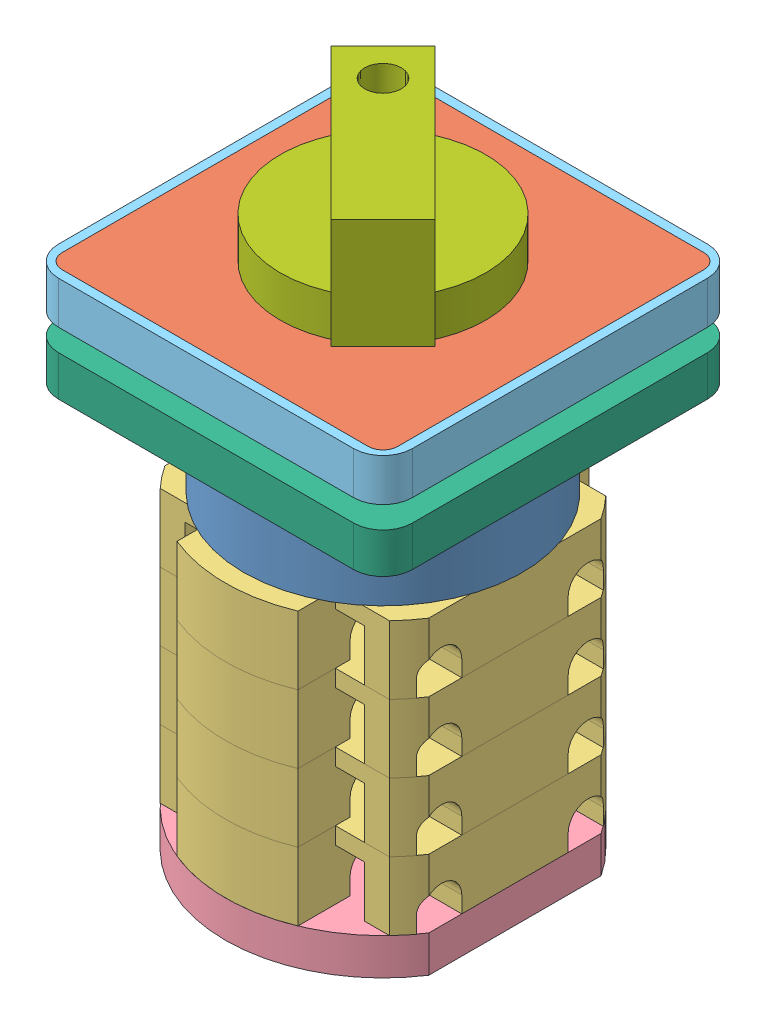
SolidWorks assembly CA10-A223, configuration Varsayılan. Lengths in mm.
Overall size (50.74 91.1 50.74).
10 component instances, 7 part files, 17 mates.
Components (placement in the parent):
- GOBEK-1: GOBEK [Varsayılan] at (-42.8429 14.9646 0) size (38 33.5 38)
- CAM ETIKET-1: CAM ETIKET [Varsayılan] at (-42.8429 27.7646 0) size (45.8 1.5 45.8)
- DILIM-1: DILIM [Varsayılan] at (-42.8429 -7.3354 0) x (-1 0 0) z (0 0 1) size (36.4 9.3 43)
- DILIMKAPAK-1: DILIMKAPAK [Varsayılan] at (-42.8429 -35.2354 0) size (36 5 43)
- DISKAPAK-1: DISKAPAK [Varsayılan] at (-42.8429 23.4646 0) size (48.3 5.8 48.3)
- GOBEKKAPAK-1: GOBEKKAPAK [Varsayılan] at (-42.8429 14.9646 0) size (48.3 5.5 48.3)
- PakoMandalı-1: PakoMandalı [Varsayılan] at (-42.8429 34.8646 0) x (0.707107 0 -0.707107) z (0.707107 0 0.707107) size (28 21.6 37.6)
- DILIM-2: DILIM [Varsayılan] at (-42.8429 -16.6354 0) x (-1 0 0) z (0 0 1) size (36.4 9.3 43)
- DILIM-3: DILIM [Varsayılan] at (-42.8429 -25.9354 0) x (-1 0 0) z (0 0 1) size (36.4 9.3 43)
- DILIM-5: DILIM [Varsayılan] at (-42.8429 -35.2354 0) x (-1 0 0) z (0 0 1) size (36.4 9.3 43)
Mates (geometry in assembly coordinates):
- Eş Merkezli1: concentric anti-aligned: cylinder of GOBEK-1 through (-58.3429 4.9646 0) axis (0 1 0) radius 2; cylinder of GOBEKKAPAK-1 through (-58.3429 20.4646 0) axis (0 -1 0) radius 2.1
- Eş Merkezli2: concentric anti-aligned: cylinder of GOBEK-1 through (-27.3429 4.9646 0) axis (0 1 0) radius 2; cylinder of GOBEKKAPAK-1 through (-27.3429 20.4646 0) axis (0 -1 0) radius 2.1
- Uzaklık1: distance = 3 mm anti-aligned: plane of DISKAPAK-1 through (-22.6929 23.4646 20.15) normal (0 -1 0); plane of GOBEKKAPAK-1 through (-62.9929 20.4646 20.15) normal (0 1 0)
- Çakışık2: coincident aligned: plane of CAM ETIKET-1 through (-21.9429 29.2646 20.9) normal (0 1 0); plane of DISKAPAK-1 through (-22.6929 29.2646 20.15) normal (0 1 0)
- Eş Merkezli3: concentric aligned: cylinder of CAM ETIKET-1 through (-42.8429 29.2646 0) axis (0 -1 0) radius 12; cylinder of DISKAPAK-1 through (-42.8429 29.2646 0) axis (0 -1 0) radius 7.1
- Eş Merkezli4: concentric aligned: cylinder of DISKAPAK-1 through (-42.8429 29.2646 0) axis (0 -1 0) radius 7.1; cylinder of PakoMandalı-1 through (-42.8429 50.8646 0) axis (0 -1 0) radius 2.5
- Çakışık3: coincident anti-aligned: plane of DISKAPAK-1 through (-22.6929 29.2646 20.15) normal (0 1 0); plane of PakoMandalı-1 through (-42.8429 29.2646 0) normal (0 -1 0)
- Eş Merkezli5: concentric aligned: cylinder of DISKAPAK-1 through (-62.9929 29.2646 -20.15) axis (0 -1 0) radius 4; cylinder of GOBEKKAPAK-1 through (-62.9929 20.4646 -20.15) axis (0 -1 0) radius 4
- Eş Merkezli6: concentric aligned: cylinder of DISKAPAK-1 through (-22.6929 29.2646 20.15) axis (0 -1 0) radius 4; cylinder of GOBEKKAPAK-1 through (-22.6929 20.4646 20.15) axis (0 -1 0) radius 4
- Çakışık4: coincident anti-aligned: plane of GOBEK-1 through (-42.8429 1.9646 0) normal (0 -1 0); plane of DILIM-1 through (-42.8429 1.9646 0) normal (0 1 0)
- Genişlik1: width anti-aligned: plane of DILIM-1 through (-24.8429 1.9646 11.758) normal (1 0 0); plane of DILIM-1 through (-60.8429 1.9646 11.758) normal (-1 0 0); plane of GOBEKKAPAK-1 through (-66.9929 20.4646 20.15) normal (-1 0 0); plane of GOBEKKAPAK-1 through (-18.6929 20.4646 20.15) normal (1 0 0)
- Genişlik2: width anti-aligned: plane of GOBEKKAPAK-1 through (-62.9929 20.4646 24.15) normal (0 0 1); plane of GOBEKKAPAK-1 through (-62.9929 20.4646 -24.15) normal (0 0 -1); plane of DILIM-1 through (-27.2004 1.9646 -14.75) normal (0 0 -1); plane of DILIM-1 through (-27.2004 1.9646 14.75) normal (0 0 1)
- Çakışık6: coincident anti-aligned: plane of GOBEK-1 through (-42.8429 14.9646 0) normal (0 1 0); plane of GOBEKKAPAK-1 through (-62.9929 14.9646 20.15) normal (0 -1 0)
- Açı1: planar angle = 0.785398 rad anti-aligned: plane of PakoMandalı-1 through (-46.3785 34.8646 3.5355) normal (-0.707107 0 0.707107); plane of DISKAPAK-1 through (-18.6929 29.2646 20.15) normal (1 0 0)
- Çakışık7: coincident anti-aligned: plane of DILIMKAPAK-1 through (-42.8429 -35.2354 0) normal (0 1 0); plane of DILIM-5 through (-42.8429 -35.2354 0) normal (0 -1 0)
- Genişlik3: width anti-aligned: plane of DILIM-1 through (-24.8429 1.9646 11.758) normal (1 0 0); plane of DILIM-1 through (-60.8429 1.9646 11.758) normal (-1 0 0); plane of DILIMKAPAK-1 through (-60.8429 -40.2354 11.758) normal (-1 0 0); plane of DILIMKAPAK-1 through (-24.8429 -40.2354 11.758) normal (1 0 0)
- Eş Merkezli7: concentric anti-aligned: cylinder of DILIMKAPAK-1 through (-42.8429 -40.2354 0) axis (0 1 0) radius 21.5; cylinder of DILIM-3 through (-42.8429 -16.6354 0) axis (0 -1 0) radius 21.5
